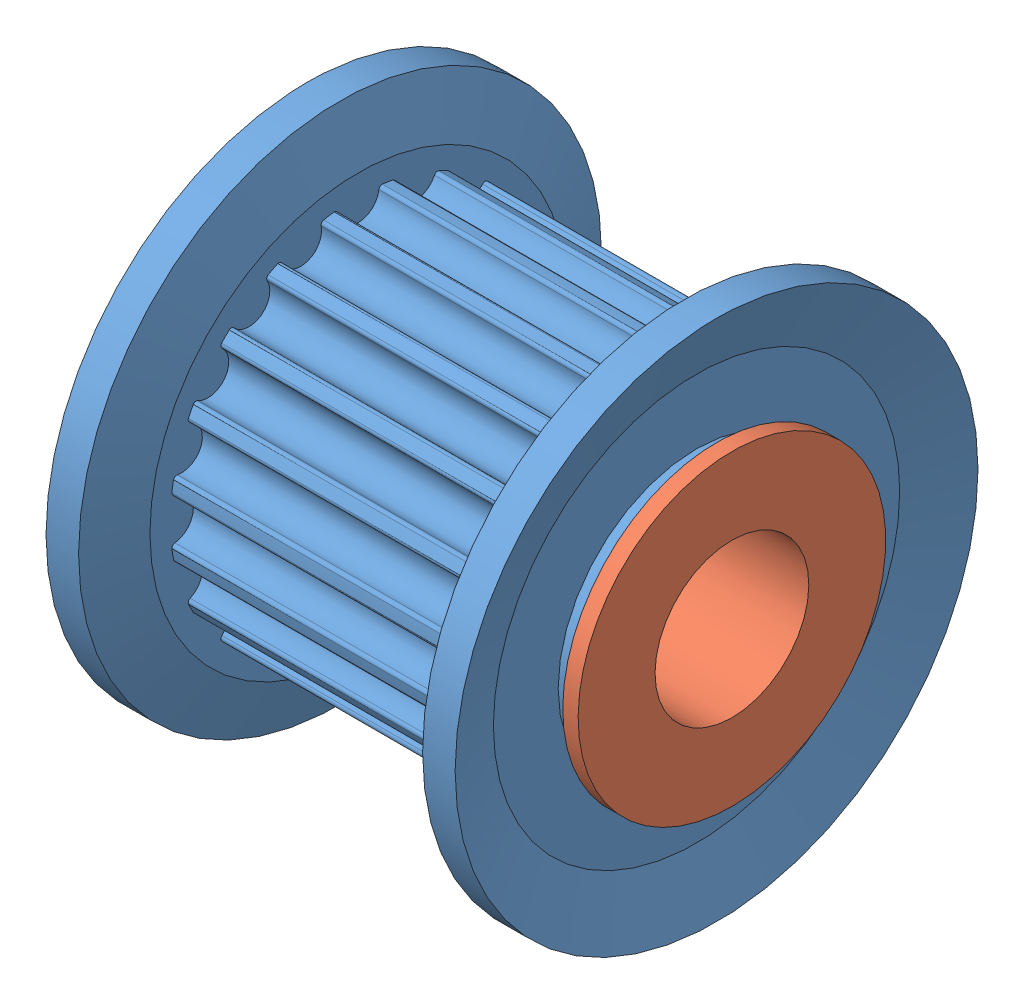
SolidWorks assembly XIdler, configuration Default. Lengths in mm.
Overall size (14.3 17 17).
3 component instances, 2 part files, 4 mates.
Components (placement in the parent):
- X Axis IdlerGPA20GT2090-A-H6-1: X Axis IdlerGPA20GT2090-A-H6 [Default] at (-1.9092 12.1708 15.1635) size (13.3 17 17)
- GFM-0506-06-1: GFM-0506-06 [Default] at (5.2408 12.1708 15.1635) x (0 -0.009943 -0.999951) z (-1 0 0) size (10 10 6)
- GFM-0506-06-2: GFM-0506-06 [Default] at (-9.0592 12.1708 15.1635) x (0 0 -1) z (1 0 0) size (10 10 6)
Mates (geometry in assembly coordinates):
- Coincident1: coincident anti-aligned: plane of X Axis IdlerGPA20GT2090-A-H6-1 through (4.7408 14.4208 15.1635) normal (1 0 0); plane of GFM-0506-06-1 through (4.7408 12.1285 10.9137) normal (-1 0 0)
- Concentric1: concentric aligned: circle of X Axis IdlerGPA20GT2090-A-H6-1; circle of GFM-0506-06-1
- Coincident2: coincident anti-aligned: plane of X Axis IdlerGPA20GT2090-A-H6-1 through (-8.5592 14.4208 15.1635) normal (-1 0 0); plane of GFM-0506-06-2 through (-8.5592 12.1708 10.9135) normal (1 0 0)
- Concentric2: concentric anti-aligned: cylinder of X Axis IdlerGPA20GT2090-A-H6-1 through (-1.9092 12.1708 15.1635) axis (1 0 0) radius 3; cylinder of GFM-0506-06-2 through (-6.0592 12.1708 15.1635) axis (-1 0 0) radius 2.5
